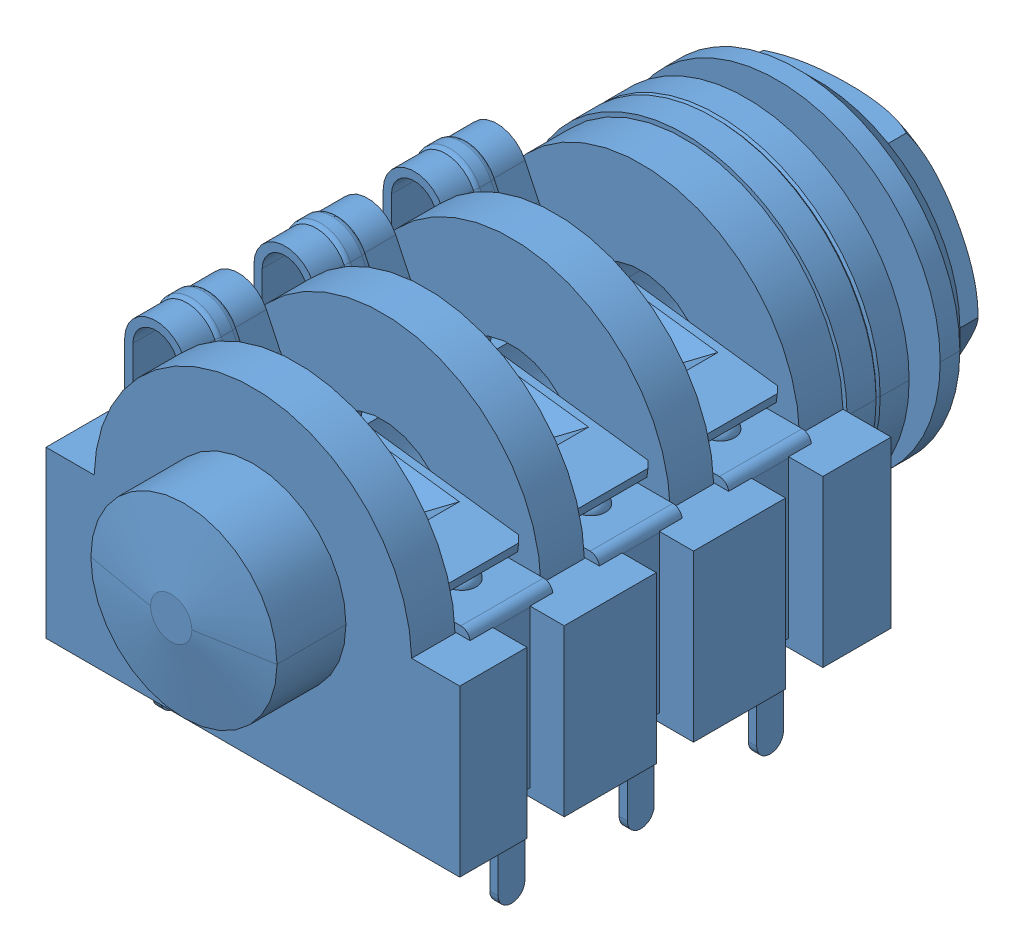
SolidWorks assembly ACJS-IH--3DModel-STEP-56544, configuration Default. Lengths in mm.
Overall size (20 19.7 33).
2 component instances, 1 part files, 0 mates.
Components (placement in the parent):
- ACJS-IH--3DModel-STEP-56544.STEP-1: ACJS-IH--3DModel-STEP-56544.STEP [Default] at origin size (20 19.7 33)
  - ACJS-IH.STEP-1: ACJS-IH.STEP [Default] at (0 0 -10.45) size (20 19.7 33)
